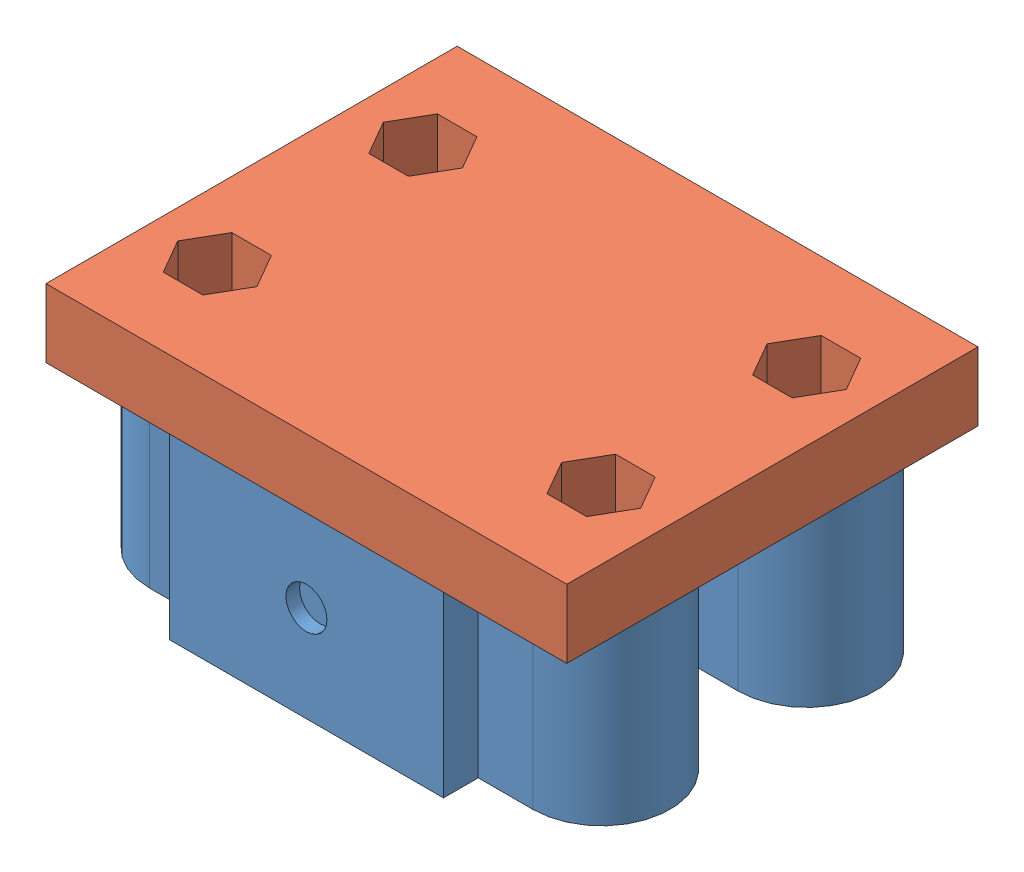
SolidWorks assembly pot-assm, configuration Default. Lengths in mm.
Overall size (38 18 30).
2 component instances, 2 part files, 0 mates.
Components (placement in the parent):
- pot-holder-1: pot-holder [Default] at (23.4326 20.2517 15.0557) size (38 13 30)
- Part1^pot-assm-1: Part1^pot-assm [Default] at origin size (38 5 30) (virtual)
